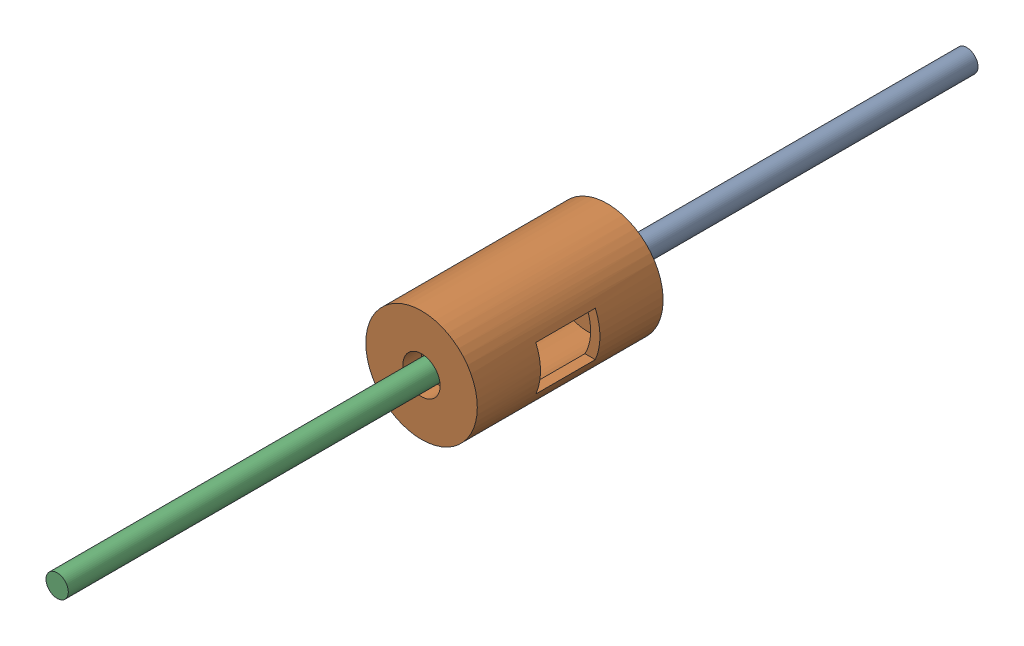
SolidWorks assembly powertrain, configuration Default. Lengths in mm.
Overall size (30 30 244.8).
3 component instances, 2 part files, 2 mates.
Components (placement in the parent):
- axle_standin-1: axle_standin [Default] at (2.9291 13.1579 -93.9581) size (6 6 101.6)
- differential_housing-1: differential_housing [Default] at (-0.935 13.2699 7.7777) size (30 30 50)
- axle_standin-2: axle_standin [Default] at (2.9291 13.1579 49.2412) x (-0.921195 -0.389101 0) z (0 0 1) size (6 6 101.6)
Mates (geometry in assembly coordinates):
- Concentric2: concentric aligned: cylinder of differential_housing-1 through (2.9291 13.1579 162.7777) axis (0 0 -1) radius 5; cylinder of axle_standin-2 through (2.9291 13.1579 150.8412) axis (0 0 -1) radius 3
- Concentric4: concentric aligned: cylinder of axle_standin-1 through (2.9291 13.1579 7.6419) axis (0 0 -1) radius 3; cylinder of differential_housing-1 through (2.9291 13.1579 162.7777) axis (0 0 -1) radius 5
